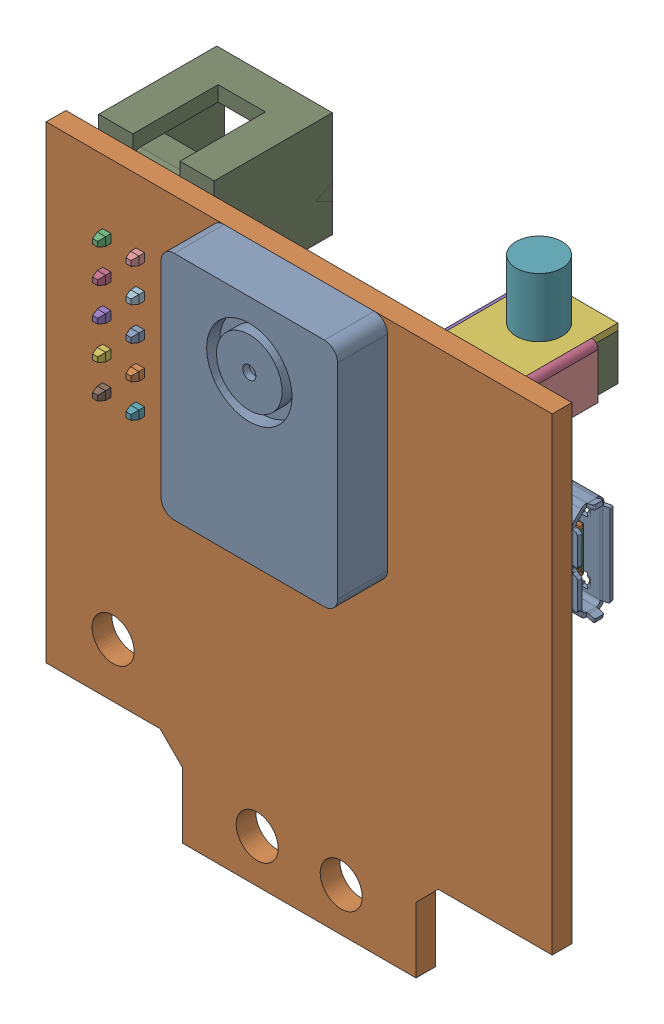
SolidWorks assembly Pixy 2, configuration Default. Lengths in mm.
Overall size (39.17 46.9 15.65).
7 component instances, 6 part files, 22 mates.
Components (placement in the parent):
- pixy-1: pixy [Default] x (1 0 0) z (0 -1 0) size (38.55 5.3 42.4)
- capacitor-1: capacitor [По умолчанию] at (-1.8911 -10.6395 0) x (-1 0 0) z (0 0 -1) size (7.71 6.82 6.76)
- micro usb-1: micro usb [По умолчанию] at (16.275 6.9 0) x (1 0 0) z (0 0 -1) size (5.84 7.77 3.4)
- DS1013-10SSiB-1: DS1013-10SSiB [Default] at (-12.105 12.63 -0.7) x (0 -1 0) z (0 0 -1) size (20.6 9.1 12.4)
- DS1022-1x3RD61-1: DS1022-1x3RD61 [По умолчанию] at (-10.575 -4.5 -0.32) x (0 -1 0) z (-1 0 0) size (7.62 10.35 5.5)
- DS1022-1x3RD61-2: DS1022-1x3RD61 [По умолчанию] at (-15.575 -9.58 -0.32) x (0 1 0) z (1 0 0) size (7.62 10.35 5.5)
- button-1: button [Default] at (15.775 17.35 0) x (1 0 0) z (0 1 0) size (7 7 11.5)
Mates (geometry in assembly coordinates):
- Совпадение1: coincident: plane of pixy-1 through (0 0 0) normal (0 0 -1); plane of micro usb-1 through (16.775 15.4582 0) normal (0 0 1)
- Совпадение2: coincident: plane of pixy-1 through (0 0 0) normal (0 0 -1); plane of capacitor-1 through (-1.8827 -10.6395 0) normal (0 0 1)
- Расстояние1: distance = 10.5 mm: plane of pixy-1 through (-8.9 -24.55 1.5) normal (0 -1 0); plane of capacitor-1 through (1.2173 -14.05 0) normal (0 -1 0)
- Расстояние2: distance = 14 mm: plane of capacitor-1 through (-5.275 -12.7646 0) normal (-1 0 0); plane of pixy-1 through (-19.275 17.85 1.5) normal (-1 0 0)
- Расстояние3: distance = 7.2 mm: plane of micro usb-1 through (16.775 10.65 -5.6597) normal (0 1 0); plane of pixy-1 through (-19.275 17.85 1.5) normal (0 1 0)
- Совпадение6: coincident: line of pixy-1 through (19.275 17.85 0) axis (0 -1 0); line of micro usb-1 through (19.275 6.9029 0) axis (0 1 0)
- Расстояние4: distance = 1 mm: plane of pixy-1 through (0 0 0) normal (0 0 -1); plane of DS1013-10SSiB-1 through (-12.105 12.63 -1) normal (0 0 1)
- Совпадение8: coincident: plane of pixy-1 through (-19.275 17.85 1.5) normal (0 1 0); plane of DS1013-10SSiB-1 through (-17.775 17.85 -1) normal (0 1 0)
- Расстояние5: distance = 1.5 mm: plane of DS1013-10SSiB-1 through (-17.775 -2.75 -1) normal (-1 0 0); plane of pixy-1 through (-19.275 17.85 1.5) normal (-1 0 0)
- Совпадение10: coincident: plane of pixy-1 through (0 0 0) normal (0 0 -1); plane of DS1022-1x3RD61-1 through (-10.575 -4.18 0) normal (0 0 1)
- Параллельность1: parallel: plane of pixy-1 through (-19.275 17.85 1.5) normal (-1 0 0); plane of DS1022-1x3RD61-1 through (-10.575 -5.1853 -4.35) normal (1 0 0)
- Совпадение11: coincident: plane of DS1022-1x3RD61-1 through (-13.075 -3.8147 -4.35) normal (-1 0 0); plane of DS1022-1x3RD61-2 through (-13.075 -5.1853 -4.35) normal (1 0 0)
- Совпадение12: coincident: plane of DS1022-1x3RD61-1 through (-10.575 -4.5 -4.35) normal (0 0 -1); plane of DS1022-1x3RD61-2 through (-15.575 -4.5 -4.35) normal (0 0 -1)
- Совпадение13: coincident: plane of DS1022-1x3RD61-1 through (-11.075 -3.23 -4.35) normal (0 1 0); plane of DS1022-1x3RD61-2 through (-13.575 -3.23 -4.35) normal (0 1 0)
- Расстояние6: distance = 3.7 mm: plane of DS1022-1x3RD61-2 through (-15.575 -3.8147 -4.35) normal (-1 0 0); plane of pixy-1 through (-19.275 17.85 1.5) normal (-1 0 0)
- Расстояние7: distance = 7 mm: plane of DS1022-1x3RD61-2 through (-15.075 -10.85 -4.35) normal (0 -1 0); plane of pixy-1 through (-19.275 -17.85 1.5) normal (0 -1 0)
- Совпадение16: coincident: plane of pixy-1 through (-19.275 17.85 1.5) normal (0 1 0); plane of button-1 through (15.775 17.85 0) normal (0 1 0)
- Совпадение17: coincident: plane of pixy-1 through (0 0 0) normal (0 0 -1); plane of button-1 through (16.275 17.35 0) normal (0 0 1)
- Расстояние8: distance = 3 mm: plane of button-1 through (16.275 17.35 0) normal (1 0 0); plane of pixy-1 through (19.275 17.85 1.5) normal (1 0 0)
- Параллельность3: parallel: plane of pixy-1 through (0 0 1.5) normal (0 0 1); plane of assembly through (0 0 0) normal (0 0 1)
- Совпадение19: coincident: point of pixy-1; point of assembly
- Параллельность4: parallel: plane of pixy-1 through (19.275 17.85 1.5) normal (1 0 0); plane of assembly through (0 0 0) normal (1 0 0)
